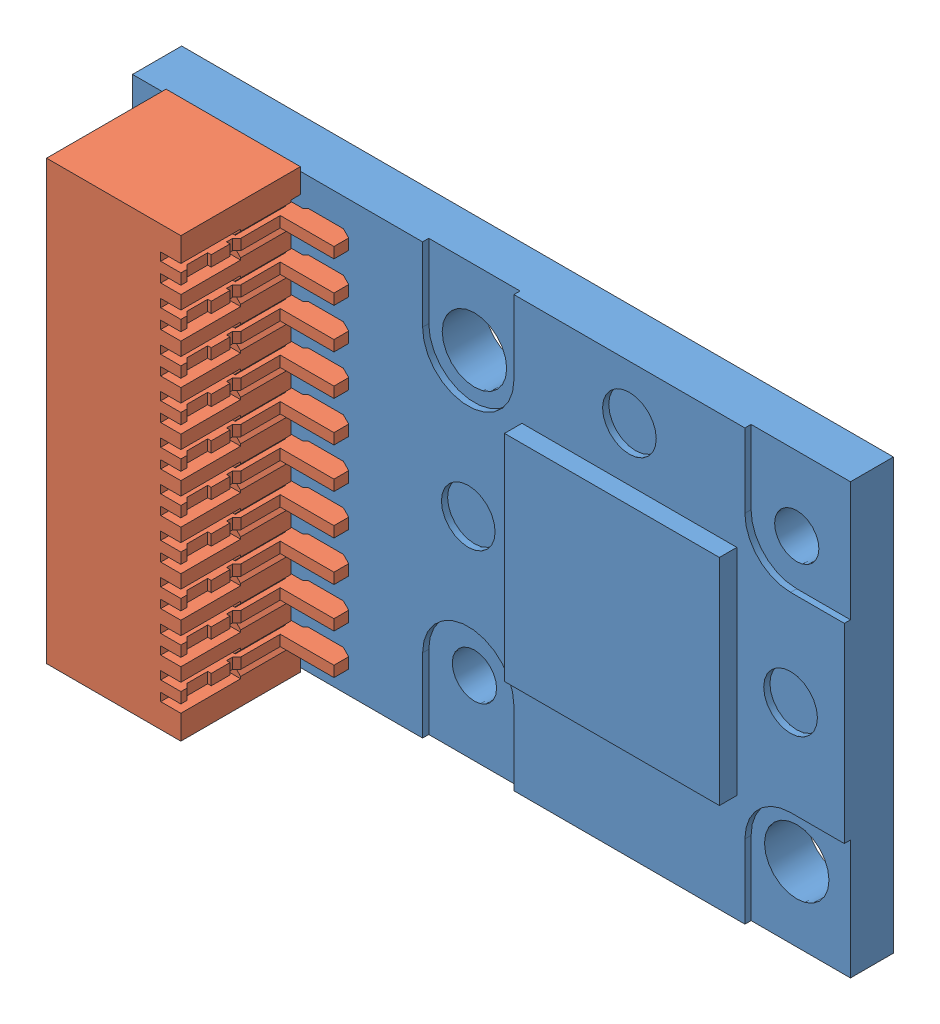
SolidWorks assembly PT54TE, configuration Default. Lengths in mm.
Overall size (26.5 16.3 6.28).
2 component instances, 2 part files, 3 mates.
Components (placement in the parent):
- LED Body-1: LED Body [Default] at (10.1323 13.8058 18.9899) size (26.5 16 2.48)
- LED Connector-1: LED Connector [Default] at (0.2573 13.8058 23.0449) x (0 -1 0) z (0 0 -1) size (16.3 7.75 4.45)
Mates (geometry in assembly coordinates):
- Coincident1: coincident anti-aligned: plane of LED Body-1 through (21.3823 19.0558 20.8199) normal (0 0 1); plane of LED Connector-1 through (0.2573 13.8058 20.8199) normal (0 0 -1)
- Distance1: distance = 0.5 mm aligned: plane of LED Connector-1 through (-2.6177 5.6558 25.2699) normal (-1 0 0); plane of LED Body-1 through (-3.1177 21.8058 20.5899) normal (-1 0 0)
- Coincident3: coincident anti-aligned: plane of LED Body-1 through (10.1323 13.8058 18.9899) normal (0 1 0); plane of LED Connector-1
